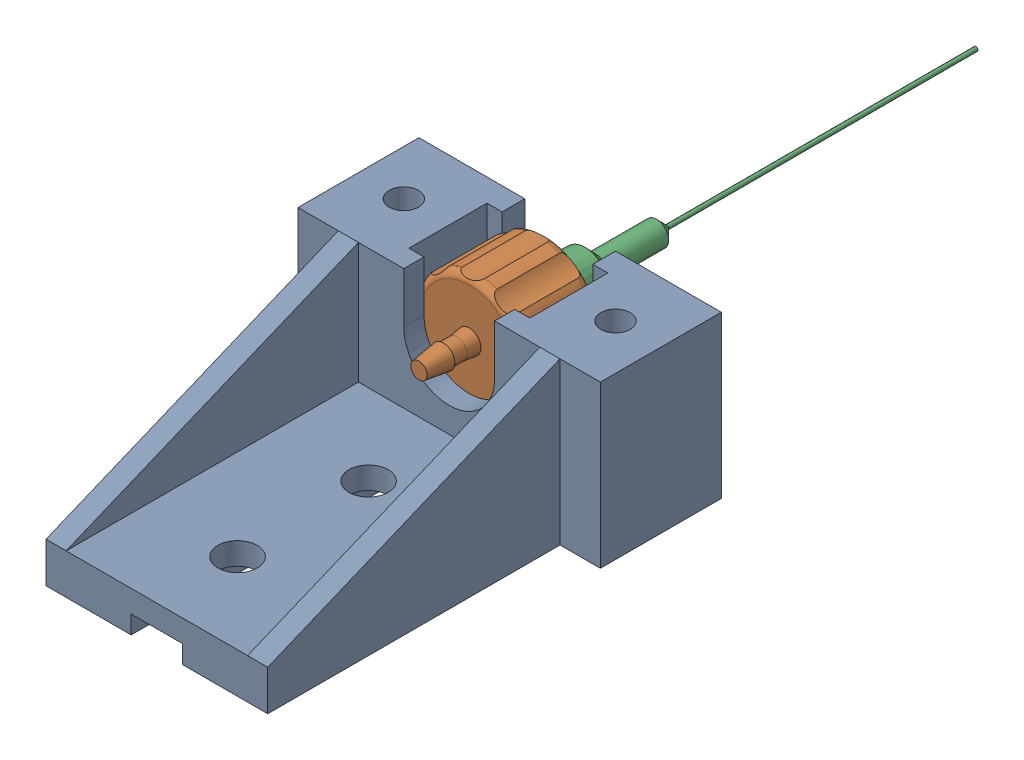
SolidWorks assembly NeedleLuerHolder, configuration Default. Lengths in mm.
Overall size (30 18.71 81.26).
3 component instances, 3 part files, 4 mates.
Components (placement in the parent):
- luerholder-1: luerholder [Default] at origin size (30 16 41)
- needleluer-1: needleluer [Default] at (9.7194 36 -2) x (-0.837169 0.546944 0) z (-0.546944 -0.837169 0) size (11.23 15.1 11.08)
- needle-1: needle [Default] at (9.7194 36 -3.2) x (1 0 0) z (0 0 -1) size (6.67 6.67 49.06)
Mates (geometry in assembly coordinates):
- Concentric6039: concentric aligned: cylinder of luerholder-1 through (9.7194 36 -9.75) axis (0 0 1) radius 6; cylinder of needleluer-1 through (9.7194 36 -9.6) axis (0 0 1) radius 5.535
- Coincident12554: coincident anti-aligned: plane of luerholder-1 through (9.7194 36 -2) normal (0 0 -1); plane of needleluer-1 through (9.7194 36 -2) normal (0 0 1)
- Coincident12555: coincident anti-aligned: plane of needle-1 through (9.7194 36 -3.2) normal (0 0 1); plane of needleluer-1 through (9.7194 36 -3.2) normal (0 0 -1)
- Concentric6040: concentric anti-aligned: cylinder of needle-1 through (9.7194 36 -52.26) axis (0 0 -1) radius 3.335; cylinder of needleluer-1 through (9.7194 36 -9.6) axis (0 0 1) radius 5.535
